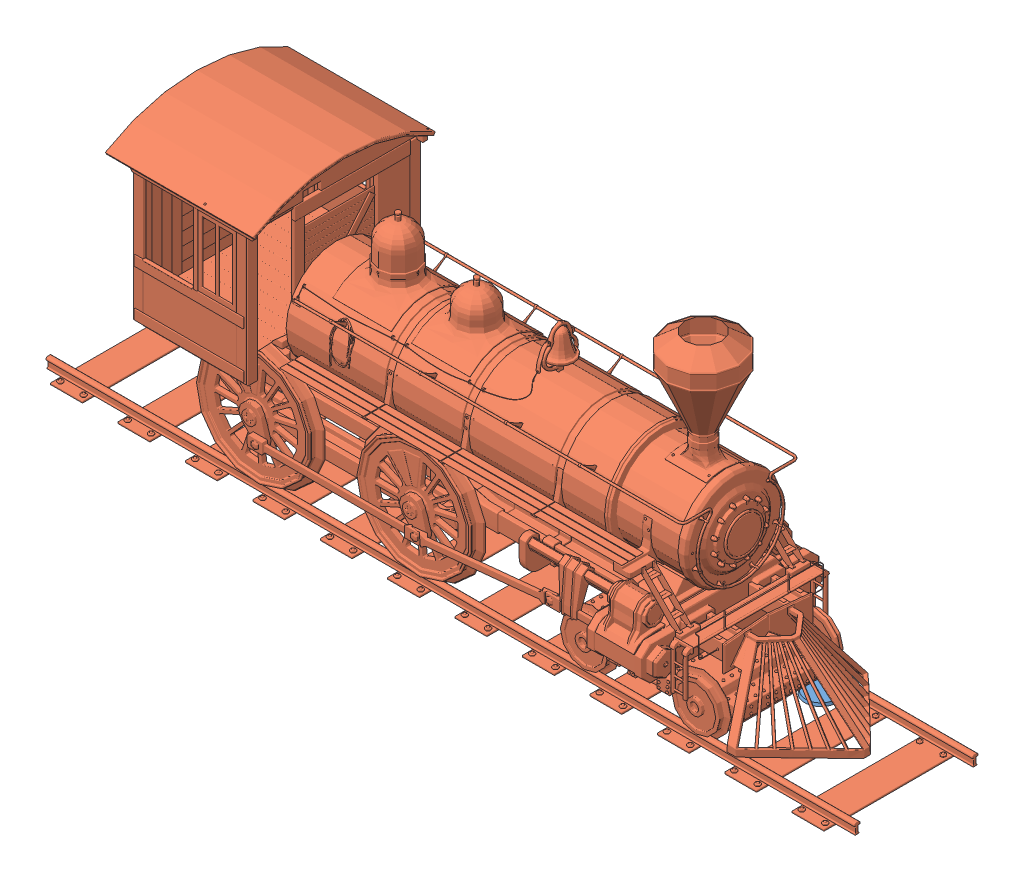
SolidWorks assembly Assem1, configuration Default. Lengths in mm.
Overall size (1258.87 709.15 478.96).
2 component instances, 2 part files, 0 mates.
Components (placement in the parent):
- BASE-1: BASE [Default] at origin size (50 4 50)
- Loco-1: Loco [Default] at (-442.5296 466.6912 311.6816) size (1258.87 470.1 285.85)
